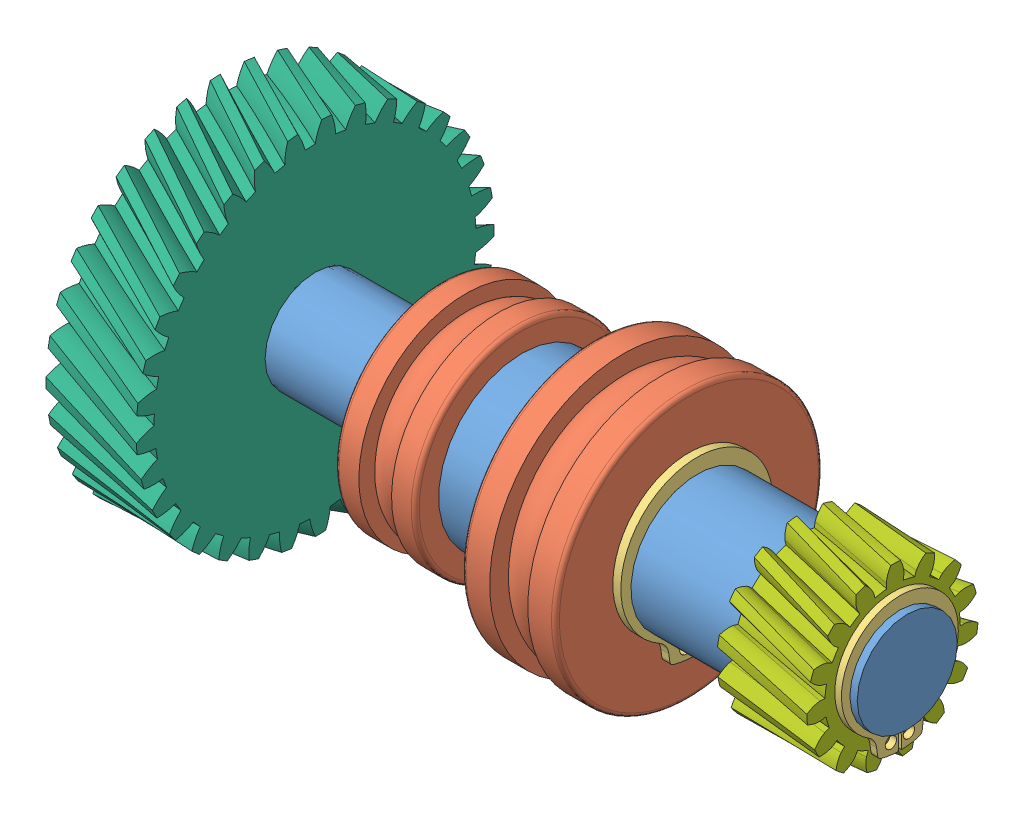
SolidWorks assembly ASSEMBLEY HELICAL SHAFT SLDASM, configuration Default. Lengths in mm.
Overall size (104.1 58.27 53.67).
11 component instances, 7 part files, 24 mates.
Components (placement in the parent):
- shaft helical-1: shaft helical [Default] at (-28.8466 7.986 9.7964) size (104.1 25 25)
- thrust ball bearing_68_skf-1: thrust ball bearing_68_skf [SKF - 51202 - 10,SI,NC,10_68] at (-40.4966 7.986 9.7964) x (1 0 0) z (0 0.148476 0.988916) size (12 32 32)
- thrust ball bearing_68_skf-2: thrust ball bearing_68_skf [SKF - 51204 - 10,SI,NC,10_68] at (-16.4966 7.986 9.7964) size (14 40 40)
- circlip for shafts normal_din-1: circlip for shafts normal_din [Circlip DIN 471 - 15 x 1] at (-46.4966 7.986 9.7964) x (0 -0.03666 -0.999328) z (1 0 0) size (17.51 20.1 1)
- circlip for shafts normal_din-2: circlip for shafts normal_din [Circlip DIN 471 - 20 x 1.2] at (-8.2966 7.986 9.7964) x (0 0 -1) z (1 0 0) size (22.81 25.6 1.2)
- circlip for shafts normal_din-3: circlip for shafts normal_din [Circlip DIN 471 - 12 x 1] at (-78.9966 7.986 9.7964) x (0 0.119154 -0.992876) z (1 0 0) size (14.08 16.6 1)
- circlip for shafts normal_din-4: circlip for shafts normal_din [Circlip DIN 471 - 15 x 1] at (22.1034 7.986 9.7964) x (0 0 -1) z (1 0 0) size (17.51 20.1 1)
- charkhhdande rast helical-1: charkhhdande rast helical [Default] at (13.5034 14.986 9.7964) x (0 0 1) z (-1 0 0) size (5 5 6)
- charkhhdande chap helical-1: charkhhdande chap helical [Default] at (-65.4966 12.486 9.7964) x (0 0 1) z (-1 0 0) size (6 4 8)
- helicaL-pele1 &2-gear-3: helicaL-pele1 &2-gear [Default] at (-65.4966 7.986 9.7964) x (0 0 1) z (-1 0 0) size (53.67 58.27 13.53)
- helical-pele1 &2-pinion-2: helical-pele1 &2-pinion [Default] at (7.5034 7.986 9.7964) x (0 0 -1) z (1 0 0) size (25.73 27.15 13.54)
Mates (geometry in assembly coordinates):
- Concentric1: concentric aligned: cylinder of shaft helical-1 through (-80.8966 7.986 9.7964) axis (-1 0 0) radius 7.5; cylinder of thrust ball bearing_68_skf-1 through (-5.5716 7.986 9.7964) axis (-1 0 0) radius 7.5
- Coincident1: coincident anti-aligned: plane of shaft helical-1 through (-34.4966 15.486 9.7964) normal (-1 0 0); plane of thrust ball bearing_68_skf-1 through (-34.4966 15.9962 8.5937) normal (1 0 0)
- Concentric2: concentric aligned: cylinder of shaft helical-1 through (-80.8966 7.986 9.7964) axis (-1 0 0) radius 10; cylinder of thrust ball bearing_68_skf-2 through (18.4284 7.986 9.7964) axis (-1 0 0) radius 10
- Coincident2: coincident anti-aligned: plane of shaft helical-1 through (-23.4966 20.486 9.7964) normal (1 0 0); plane of thrust ball bearing_68_skf-2 through (-23.4966 18.586 9.7964) normal (-1 0 0)
- Concentric3: concentric anti-aligned: cylinder of shaft helical-1 through (-80.8966 7.986 9.7964) axis (-1 0 0) radius 7.15; cylinder of circlip for shafts normal_din-1 through (-47.4966 7.986 9.7964) axis (1 0 0) radius 7.15
- Coincident3: coincident anti-aligned: plane of shaft helical-1 through (-46.4966 15.486 9.7964) normal (-1 0 0); plane of circlip for shafts normal_din-1 through (-46.4966 7.986 9.7964) normal (1 0 0)
- Concentric4: concentric anti-aligned: cylinder of shaft helical-1 through (-80.8966 7.986 9.7964) axis (-1 0 0) radius 9.5; cylinder of circlip for shafts normal_din-2 through (-9.4966 7.986 9.7964) axis (1 0 0) radius 9.5
- Coincident4: coincident anti-aligned: plane of shaft helical-1 through (-9.4966 17.986 9.7964) normal (1 0 0); plane of circlip for shafts normal_din-2 through (-9.4966 7.986 9.7964) normal (-1 0 0)
- Concentric6: concentric anti-aligned: cylinder of shaft helical-1 through (-80.8966 7.986 9.7964) axis (-1 0 0) radius 5.75; cylinder of circlip for shafts normal_din-3 through (-79.9966 7.986 9.7964) axis (1 0 0) radius 5.75
- Coincident5: coincident anti-aligned: plane of shaft helical-1 through (-78.9966 13.986 9.7964) normal (-1 0 0); plane of circlip for shafts normal_din-3 through (-78.9966 7.986 9.7964) normal (1 0 0)
- Concentric7: concentric anti-aligned: cylinder of shaft helical-1 through (-80.8966 7.986 9.7964) axis (-1 0 0) radius 7.15; cylinder of circlip for shafts normal_din-4 through (21.1034 7.986 9.7964) axis (1 0 0) radius 7.15
- Coincident6: coincident anti-aligned: plane of shaft helical-1 through (22.1034 15.486 9.7964) normal (-1 0 0); plane of circlip for shafts normal_din-4 through (22.1034 7.986 9.7964) normal (1 0 0)
- Coincident7: coincident anti-aligned: plane of shaft helical-1 through (13.5034 15.486 12.2964) normal (0 0 -1); plane of charkhhdande rast helical-1 through (7.5034 12.486 12.2964) normal (0 0 1)
- Coincident8: coincident anti-aligned: plane of shaft helical-1 through (13.5034 12.486 12.2964) normal (0 1 0); plane of charkhhdande rast helical-1 through (7.5034 12.486 7.2964) normal (0 -1 0)
- Coincident9: coincident anti-aligned: plane of shaft helical-1 through (7.5034 17.986 9.7964) normal (1 0 0); plane of charkhhdande rast helical-1 through (7.5034 14.986 9.7964) normal (-1 0 0)
- Coincident10: coincident anti-aligned: plane of shaft helical-1 through (-65.4966 13.986 9.7964) normal (-1 0 0); plane of charkhhdande chap helical-1 through (-65.4966 12.486 9.7964) normal (1 0 0)
- Coincident11: coincident anti-aligned: plane of shaft helical-1 through (-73.4966 10.486 6.7964) normal (0 0 1); plane of charkhhdande chap helical-1 through (-73.4966 10.486 6.7964) normal (0 0 -1)
- Coincident13: coincident anti-aligned: plane of shaft helical-1 through (-73.4966 10.486 6.7964) normal (0 1 0); plane of charkhhdande chap helical-1 through (-73.4966 10.486 6.7964) normal (0 -1 0)
- Concentric11: concentric anti-aligned: cylinder of shaft helical-1 through (-80.8966 7.986 9.7964) axis (-1 0 0) radius 6; cylinder of helicaL-pele1 &2-gear-3 through (-79.0092 7.986 9.7964) axis (1 0 0) radius 6
- Coincident14: coincident anti-aligned: plane of charkhhdande chap helical-1 through (-73.4966 10.486 12.7964) normal (0 0 1); plane of helicaL-pele1 &2-gear-3 through (-71.4966 13.1822 12.7964) normal (0 0 -1)
- Coincident15: coincident anti-aligned: plane of shaft helical-1 through (-65.4966 13.986 9.7964) normal (-1 0 0); plane of helicaL-pele1 &2-gear-3 through (-65.4966 7.986 9.7964) normal (1 0 0)
- Concentric12: concentric: cylinder of shaft helical-1 through (-80.8966 7.986 9.7964) axis (-1 0 0) radius 7.5; cylinder of helical-pele1 &2-pinion-2 through (21.0225 7.986 9.7964) axis (-1 0 0) radius 7.5
- Coincident16: coincident: plane of charkhhdande rast helical-1 through (7.5034 12.486 12.2964) normal (0 0 1); plane of helical-pele1 &2-pinion-2 through (13.5034 15.0571 12.2964) normal (0 0 -1)
- Coincident17: coincident anti-aligned: plane of shaft helical-1 through (7.5034 17.986 9.7964) normal (1 0 0); plane of helical-pele1 &2-pinion-2 through (7.5034 7.986 9.7964) normal (-1 0 0)
